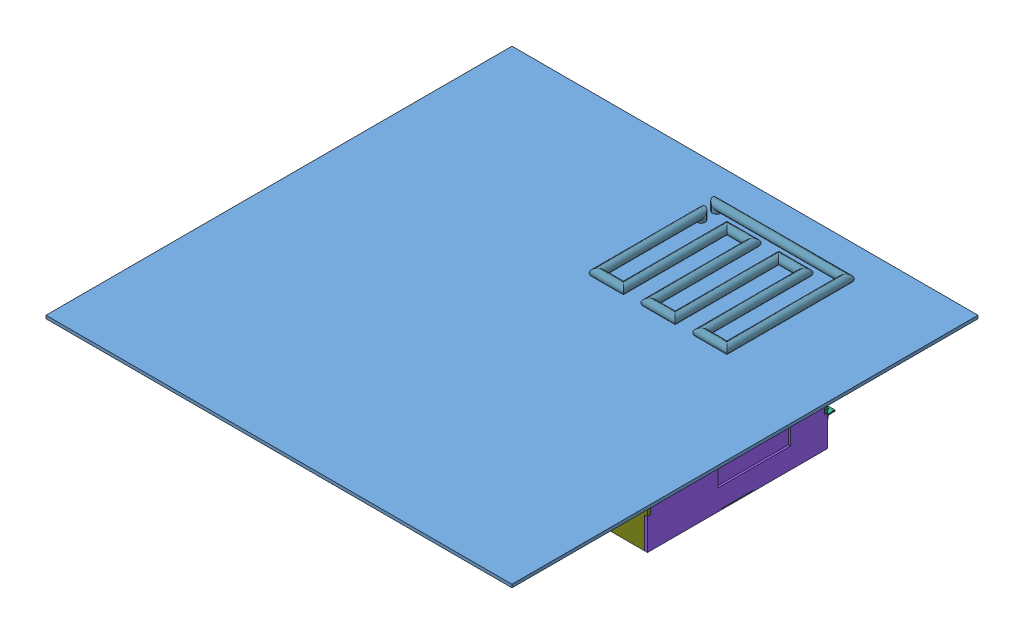
SolidWorks assembly House_Modular, configuration Default. Lengths in mm.
Overall size (450 127.63 450).
180 component instances, 85 part files, 139 mates.
Components (placement in the parent):
- ground-2: ground [Default] at (29.9033 0 -57.0618) x (1 0 0) z (0 1 0) size (450 450 3)
- door-1: door [Default] at (-96.5829 43.9908 -3) x (-1 0 0) z (0 0 1) size (30 61 3)
- door-2: door [Default] at (-38.2325 43.9908 -155.3504) x (0 0 -1) z (-1 0 0) size (30 61 3)
- sg90-1: sg90 [Default] at (138.7675 -45.998 -166.9) x (0 -1 0) z (-1 0 0) size (31.9 29.9 11.8)
- door-3: door [Default] at (-41.2325 43.9908 -18.6496) x (0 0 1) z (1 0 0) size (30 61 3)
- ESP32-CAM-1: ESP32-CAM [Default] at (34.3709 -59.4874 -9.0698) x (1 0 0) z (0 -1 0) size (40.5 18.58 27)
- 25x25x7_fan-1: 25x25x7_fan [Default] at (-17.2845 -26.1253 -169.7289) x (1 0 0) z (0 0 -1) size (25.78 25.81 8)
- TCRT5000-1: TCRT5000 [Predeterminado] at (33.7675 -28.3 -7.5) x (0 -1 0) z (0 0 1) size (14 36.97 13.8)
- bedroom_window-1: bedroom_window [Default] at (-82.9325 -48.4 -2) x (1 0 0) z (0 1 0) size (30 1 21)
- living_room_window-2: living_room_window [Default] at (139.7675 -61.9959 -92.4856) x (0 0 -1) z (0 1 0) size (70 1 25)
- SG90 plastic Horn-1: SG90 plastic Horn [Default] at (132.8675 -51.898 -138.2) x (0.279531 -0.960137 0) z (-0.960137 -0.279531 0) size (19.4 4 7.07)
- irf520n_module_asm-1: irf520n_module_asm [Default] at (0.8196 -70.3815 -175.6) x (-1 0 0) z (0 0 -1) size (34 31 21.5)
  - irf520n_module_asm.stp-1: irf520n_module_asm.stp [Default] at origin size (34 31 21.5)
    - CONECTOR_2X_AF0_ASM.stp-1: CONECTOR_2X_AF0_ASM.stp [Default] at (10.0021 9.5092 -1.5) x (1 0 0) z (0 -1 0) size (10 12.5 7.5)
      - CONEC1_AF0.stp-1: CONEC1_AF0.stp [Default] at origin size (0.5 1 0.5)
      - CONEC2_AF0.stp-1: CONEC2_AF0.stp [Default] at origin size (0.5 1 0.5)
      - CONEC3.stp-1: CONEC3.stp [Default] at origin size (4 2.5 0.5)
      - CONEC4.stp-1: CONEC4.stp [Default] at origin size (4 2.5 0.5)
      - CONEC5.stp-1: CONEC5.stp [Default] at origin size (3.8 3.8 4)
      - CONEC6.stp-1: CONEC6.stp [Default] at origin size (3.8 3.8 4)
      - CONEC7.stp-1: CONEC7.stp [Default] at origin size (10 10 7.5)
      - CONEC8.stp-1: CONEC8.stp [Default] at origin size (2.6 2.5 2.6)
      - CONEC9.stp-1: CONEC9.stp [Default] at origin size (2.6 2.5 2.6)
    - CONECTOR_2X_AF1_ASM.stp-1: CONECTOR_2X_AF1_ASM.stp [Default] at (23.4021 9.5092 -1.5) x (1 0 0) z (0 -1 0) size (10 12.5 7.5)
      - CONEC1_AF1.stp-1: CONEC1_AF1.stp [Default] at origin size (0.5 1 0.5)
      - CONEC2_AF1.stp-1: CONEC2_AF1.stp [Default] at origin size (0.5 1 0.5)
      - CONEC3.stp-1: CONEC3.stp [Default] at origin size (4 2.5 0.5)
      - CONEC4.stp-1: CONEC4.stp [Default] at origin size (4 2.5 0.5)
      - CONEC5.stp-1: CONEC5.stp [Default] at origin size (3.8 3.8 4)
      - CONEC6.stp-1: CONEC6.stp [Default] at origin size (3.8 3.8 4)
      - CONEC7.stp-1: CONEC7.stp [Default] at origin size (10 10 7.5)
      - CONEC8.stp-1: CONEC8.stp [Default] at origin size (2.6 2.5 2.6)
      - CONEC9.stp-1: CONEC9.stp [Default] at origin size (2.6 2.5 2.6)
    - IRF520_AF0_ASM.stp-1: IRF520_AF0_ASM.stp [Default] at (16.0021 9.4375 4) x (0 1 0) z (0 0 1) size (4.75 10.5 21.5)
      - IRF3808_1_AF0_ASM.stp-1: IRF3808_1_AF0_ASM.stp [Default] at origin size (0.55 3.94 6.5)
        - IRF3808_1_1_AF0.stp-1: IRF3808_1_1_AF0.stp [Default] at origin size (0.55 1.4 6.5)
        - IRF3808_1_2_AF0.stp-1: IRF3808_1_2_AF0.stp [Default] at origin size (0.55 1.4 6.5)
      - IRF3808_2_AF0.stp-1: IRF3808_2_AF0.stp [Default] at origin size (0.55 1.4 6.5)
      - IRF3808_3.stp-1: IRF3808_3.stp [Default] at origin size (1.22 10.5 12.3)
      - IRF3808_4.stp-1: IRF3808_4.stp [Default] at origin size (4.53 10.5 8.7)
    - IRF520N.stp-1: IRF520N.stp [Default] at origin size (34 25 1.6)
    - ______________6_AF0.stp-1: ______________6_AF0.stp [Default] at (23.2521 9.2592 -1.5) x (0 1 0) z (1 0 0) size (9.25 7.25 7.5)
    - LED.stp-1: LED.stp [Default] at (23.3771 10.0092 0) x (0 1 0) z (1 0 0) size (4.01 1.01 1.32)
    - 603_RESISTOR.stp-1: 603_RESISTOR.stp [Default] at (20.6021 10.0463 0) x (0 -1 0) z (-1 0 0) size (2.36 0.61 1.02)
    - 603_RESISTOR.stp-2: 603_RESISTOR.stp [Default] at (26.1021 10.0463 0) x (0 -1 0) z (-1 0 0) size (2.36 0.61 1.02)
- irf520n_module_asm-2: irf520n_module_asm [Default] at (133.7196 -84.5092 -175.6) x (-1 0 0) z (0 0 -1) size (34 31 21.5)
  - irf520n_module_asm.stp-1: irf520n_module_asm.stp [Default] at origin size (34 31 21.5)
    - CONECTOR_2X_AF0_ASM.stp-1: CONECTOR_2X_AF0_ASM.stp [Default] at (10.0021 9.5092 -1.5) x (1 0 0) z (0 -1 0) size (10 12.5 7.5)
      - CONEC1_AF0.stp-1: CONEC1_AF0.stp [Default] at origin size (0.5 1 0.5)
      - CONEC2_AF0.stp-1: CONEC2_AF0.stp [Default] at origin size (0.5 1 0.5)
      - CONEC3.stp-1: CONEC3.stp [Default] at origin size (4 2.5 0.5)
      - CONEC4.stp-1: CONEC4.stp [Default] at origin size (4 2.5 0.5)
      - CONEC5.stp-1: CONEC5.stp [Default] at origin size (3.8 3.8 4)
      - CONEC6.stp-1: CONEC6.stp [Default] at origin size (3.8 3.8 4)
      - CONEC7.stp-1: CONEC7.stp [Default] at origin size (10 10 7.5)
      - CONEC8.stp-1: CONEC8.stp [Default] at origin size (2.6 2.5 2.6)
      - CONEC9.stp-1: CONEC9.stp [Default] at origin size (2.6 2.5 2.6)
    - CONECTOR_2X_AF1_ASM.stp-1: CONECTOR_2X_AF1_ASM.stp [Default] at (23.4021 9.5092 -1.5) x (1 0 0) z (0 -1 0) size (10 12.5 7.5)
      - CONEC1_AF1.stp-1: CONEC1_AF1.stp [Default] at origin size (0.5 1 0.5)
      - CONEC2_AF1.stp-1: CONEC2_AF1.stp [Default] at origin size (0.5 1 0.5)
      - CONEC3.stp-1: CONEC3.stp [Default] at origin size (4 2.5 0.5)
      - CONEC4.stp-1: CONEC4.stp [Default] at origin size (4 2.5 0.5)
      - CONEC5.stp-1: CONEC5.stp [Default] at origin size (3.8 3.8 4)
      - CONEC6.stp-1: CONEC6.stp [Default] at origin size (3.8 3.8 4)
      - CONEC7.stp-1: CONEC7.stp [Default] at origin size (10 10 7.5)
      - CONEC8.stp-1: CONEC8.stp [Default] at origin size (2.6 2.5 2.6)
      - CONEC9.stp-1: CONEC9.stp [Default] at origin size (2.6 2.5 2.6)
    - IRF520_AF0_ASM.stp-1: IRF520_AF0_ASM.stp [Default] at (16.0021 9.4375 4) x (0 1 0) z (0 0 1) size (4.75 10.5 21.5)
      - IRF3808_1_AF0_ASM.stp-1: IRF3808_1_AF0_ASM.stp [Default] at origin size (0.55 3.94 6.5)
        - IRF3808_1_1_AF0.stp-1: IRF3808_1_1_AF0.stp [Default] at origin size (0.55 1.4 6.5)
        - IRF3808_1_2_AF0.stp-1: IRF3808_1_2_AF0.stp [Default] at origin size (0.55 1.4 6.5)
      - IRF3808_2_AF0.stp-1: IRF3808_2_AF0.stp [Default] at origin size (0.55 1.4 6.5)
      - IRF3808_3.stp-1: IRF3808_3.stp [Default] at origin size (1.22 10.5 12.3)
      - IRF3808_4.stp-1: IRF3808_4.stp [Default] at origin size (4.53 10.5 8.7)
    - IRF520N.stp-1: IRF520N.stp [Default] at origin size (34 25 1.6)
    - ______________6_AF0.stp-1: ______________6_AF0.stp [Default] at (23.2521 9.2592 -1.5) x (0 1 0) z (1 0 0) size (9.25 7.25 7.5)
    - LED.stp-1: LED.stp [Default] at (23.3771 10.0092 0) x (0 1 0) z (1 0 0) size (4.01 1.01 1.32)
    - 603_RESISTOR.stp-1: 603_RESISTOR.stp [Default] at (20.6021 10.0463 0) x (0 -1 0) z (-1 0 0) size (2.36 0.61 1.02)
    - 603_RESISTOR.stp-2: 603_RESISTOR.stp [Default] at (26.1021 10.0463 0) x (0 -1 0) z (-1 0 0) size (2.36 0.61 1.02)
- Protoboard_with_resistors-1: Protoboard_with_resistors [Default] at (121.7903 -82.1488 -189.9712) x (-1 0 0) z (0 1 0) size (45 19.41 34.07)
  - MINIPROTOBOARD-1: MINIPROTOBOARD [Default] at (20.7748 18.9712 36.8488) size (45 9.5 34)
  - Resistor Carbon Film 0W5 L10.3 D3.8 LD0.77mm Horizontal-1: Resistor Carbon Film 0W5 L10.3 D3.8 LD0.77mm Horizontal [Default] at (29.8566 34.4712 50.6841) x (0.990749 0 -0.135704) z (0 1 0) size (19.83 3.81 9.91)
  - Resistor Carbon Film 0W5 L10.3 D3.8 LD0.77mm Horizontal-2: Resistor Carbon Film 0W5 L10.3 D3.8 LD0.77mm Horizontal [Default] at (29.9349 34.4712 31.1282) x (0.991455 0 -0.130446) z (0 1 0) size (19.83 3.81 9.91)
  - Resistor Carbon Film 0W5 L10.3 D3.8 LD0.77mm Horizontal-3: Resistor Carbon Film 0W5 L10.3 D3.8 LD0.77mm Horizontal [Default] at (29.8373 34.4712 23.175) x (0.991455 0 -0.130446) z (0 1 0) size (19.83 3.81 9.91)
  - Resistor Carbon Film 0W5 L10.3 D3.8 LD0.77mm Horizontal-4: Resistor Carbon Film 0W5 L10.3 D3.8 LD0.77mm Horizontal [Default] at (11.6938 34.4712 50.4431) x (0.991455 0 -0.130446) z (0 1 0) size (19.83 3.81 9.91)
  - Resistor Carbon Film 0W5 L10.3 D3.8 LD0.77mm Horizontal-5: Resistor Carbon Film 0W5 L10.3 D3.8 LD0.77mm Horizontal [Default] at (11.7515 34.4712 42.5299) x (0.991455 0 -0.130446) z (0 1 0) size (19.83 3.81 9.91)
  - Resistor Carbon Film 0W5 L10.3 D3.8 LD0.77mm Horizontal-6: Resistor Carbon Film 0W5 L10.3 D3.8 LD0.77mm Horizontal [Default] at (11.7518 34.4712 31.0334) x (0.991455 0 -0.130446) z (0 1 0) size (19.83 3.81 9.91)
  - Resistor Carbon Film 0W5 L10.3 D3.8 LD0.77mm Horizontal-7: Resistor Carbon Film 0W5 L10.3 D3.8 LD0.77mm Horizontal [Default] at (29.8542 34.4712 42.577) x (0.991455 0 -0.130446) z (0 1 0) size (19.83 3.81 9.91)
  - Resistor Carbon Film 0W5 L10.3 D3.8 LD0.77mm Horizontal-8: Resistor Carbon Film 0W5 L10.3 D3.8 LD0.77mm Horizontal [Default] at (11.664 34.4712 23.3005) x (0.991455 0 -0.130446) z (0 1 0) size (19.83 3.81 9.91)
- Tube-1: Tube [Default] at (-17.5325 -26.3726 -201) x (-1 0 0) z (0 0 1) size (133 43 123)
- Fan adapter-1: Fan adapter [Default] at (-43.5325 17.1277 -171) x (0 -1 0) z (0 0 -1) size (31 31 30)
- front_living_room-1: front_living_room [Default] at (-96.9752 39.2755 -3) x (-1 0 0) z (0 0 1) size (183 90 3)
- Rear_kitchen-1: Rear_kitchen [Default] at (115.9594 -3 -174) size (123 90 3)
- front_room-1: front_room [Default] at (-93.0252 40.9131 -3) x (-1 0 0) z (0 0 1) size (123 90 3)
- kitchen_window-1: kitchen_window [Default] at (-65.8325 -46.7 -173) x (0 1 0) z (-1 0 0) size (30 1 15)
- MQ-2-1: MQ-2 [Default] at (-119.0203 -70.9563 -176.6) x (-1 0 0) z (0 0 1) size (32.25 20.65 21.36)
  - MQ-2.STEP-1: MQ-2.STEP [Default] at origin size (32.25 20.65 21.36)
    - MQ-2.step.STEP-1: MQ-2.step.STEP [Default] at origin size (32.25 20.65 21.36)
      - SMP-generic.step.STEP-1: SMP-generic.step.STEP [Default] at (-6.8415 -4.3705 0.0123) x (-1 0 0) z (0 0 -1) size (7.04 5 1.51)
        - leads.step.STEP-1: leads.step.STEP [Default] at origin size (7.04 4.3 1.25)
        - SMP-generic-0.step.STEP-1: SMP-generic-0.step.STEP [Default] at origin size (4 5 1.5)
      - LED SMT.step.STEP-1: LED SMT.step.STEP [Default] at (0.6625 8.5036 0.1819) x (1 0 0) z (0 0 -1) size (4.65 1.31 0.64)
        - Component1.step.STEP-1: Component1.step.STEP [Default] at (0.0071 0.0115 0.0021) size (2 1.3 0.6)
        - LED SMT-1.step.STEP-1: LED SMT-1.step.STEP [Default] at origin size (1.21 1.3 0.62)
        - LED SMT-2.step.STEP-1: LED SMT-2.step.STEP [Default] at origin size (1.43 1.3 0.63)
        - LED SMT-3.step.STEP-1: LED SMT-3.step.STEP [Default] at origin size (1.09 0.6 0.1)
        - LED SMT-4.step.STEP-1: LED SMT-4.step.STEP [Default] at origin size (1.4 0.58 0.1)
      - LED SMT_1.step.STEP-1: LED SMT_1.step.STEP [Default] at (1.6513 -8.947 0.1758) x (1 0 0) z (0 0 -1) size (4.65 1.31 0.64)
        - Component1.step.STEP-1: Component1.step.STEP [Default] at (0.0071 0.0115 0.0021) size (2 1.3 0.6)
        - LED SMT_1-5.step.STEP-1: LED SMT_1-5.step.STEP [Default] at origin size (1.21 1.3 0.62)
        - LED SMT_1-6.step.STEP-1: LED SMT_1-6.step.STEP [Default] at origin size (1.43 1.3 0.63)
        - LED SMT_1-7.step.STEP-1: LED SMT_1-7.step.STEP [Default] at origin size (1.09 0.6 0.1)
        - LED SMT_1-8.step.STEP-1: LED SMT_1-8.step.STEP [Default] at origin size (1.4 0.58 0.1)
      - small POT.step.STEP-1: small POT.step.STEP [Default] at (-8.8072 6.1022 -0.1215) x (0 1 0) z (0 0 -1) size (7 7 6.25)
        - Component1_1.step.STEP-1: Component1_1.step.STEP [Default] at origin size (7 7 6.25)
        - Component2.step.STEP-1: Component2.step.STEP [Default] at (0 0 -0.101) size (3.49 3.49 1)
      - PCB.step.STEP-1: PCB.step.STEP [Default] at origin size (32.25 20.65 1.6)
      - sensor.step.STEP-1: sensor.step.STEP [Default] at origin size (19.68 19.68 18.01)
      - 10k ohm SMT.step.STEP-1: 10k ohm SMT.step.STEP [Default] at (-6.3738 -9.0701 0.182) x (1 0 0) z (0 0 -1) size (4.65 1.3 0.64)
      - 10k ohm SMT.step.STEP-2: 10k ohm SMT.step.STEP [Default] at (5.9398 -9.0079 0.2021) x (1 0 0) z (0 0 -1) size (4.65 1.3 0.64)
      - 10k ohm SMT.step.STEP-3: 10k ohm SMT.step.STEP [Default] at (-10.6991 1.4157 0.2498) x (-1 0 0) z (0 0 -1) size (4.65 1.3 0.64)
      - 10k ohm SMT.step.STEP-4: 10k ohm SMT.step.STEP [Default] at (12.9889 -2.6781 0.1874) x (1 0 0) z (0 0 -1) size (4.65 1.3 0.64)
      - 10k ohm SMT.step.STEP-5: 10k ohm SMT.step.STEP [Default] at (13.0248 -0.0312 0.1725) x (1 0 0) z (0 0 -1) size (4.65 1.3 0.64)
      - 10k ohm SMT.step.STEP-6: 10k ohm SMT.step.STEP [Default] at (13.1811 2.923 0.1948) x (1 0 0) z (0 0 -1) size (4.65 1.3 0.64)
      - 10k ohm SMT.step.STEP-7: 10k ohm SMT.step.STEP [Default] at (4.9611 8.4811 0.2136) x (1 0 0) z (0 0 -1) size (4.65 1.3 0.64)
- PIR SR602-2: PIR SR602 [Default] at (-39.6325 -100.1412 -80.8303) x (0 0 1) z (0 -1 0) size (16 18.89 16)
- BU-2: BU [Predeterminado] at (-78.4255 -61.637 -182) x (0 1 0) z (0 0 1) size (23.75 15.4 11)
- KY-026_flame_IR_sensor-1: KY-026_flame_IR_sensor [Default] at (-122.6825 -41 -190.03) x (0 0 1) z (0 -1 0) size (44.9 15.1 14.02)
- roof2_single_wall-1: roof2_single_wall [Default] at (-135.0442 -100.5287 -134.2016) x (0 -0.349591 0.936903) z (1 0 0) size (71.51 3 123)
- right_kitchen_outside_single_wall-1: right_kitchen_outside_single_wall [Default] at (-164.2325 134.9698 -393.8578) x (0 0 1) z (1 0 0) size (73 115 3)
- middle_wall_kitchen_single_wall-1: middle_wall_kitchen_single_wall [Default] at (-44.2325 139.1238 -352.6279) x (0 0 1) z (1 0 0) size (73 115 3)
- room_wall_single_wall-1: room_wall_single_wall [Default] at (-94.8313 -26.8319 -104.0015) x (-1 0 0) z (0 1 0) size (123 3 115)
- middle_wall_bedroom_single_wall-1: middle_wall_bedroom_single_wall [Default] at (-44.2325 139.1238 -352.6902) x (0 0 1) z (1 0 0) size (101 115 3)
- room_wall_single_wall-2: room_wall_single_wall [Default] at (-94.8313 -26.8319 -101.0015) x (-1 0 0) z (0 1 0) size (123 3 115)
- left_living_room_single_wall-1: left_living_room_single_wall [Default] at (141.7675 -31.9153 -252.4029) x (0 0 1) z (-1 0 0) size (174 90 3)
- floor_living_room_single_wall-1: floor_living_room_single_wall [Default] at (60.2675 0 -56.3991) x (0 0 1) z (1 0 0) size (174 3 183)
- transparent_roof_living_room_single_wall-1: transparent_roof_living_room_single_wall [Default] at (87.0895 -89 -51.008) x (-1 0 0) z (0 0 1) size (180 1 174)
- middle_wall_living_room_single_wall-2: middle_wall_living_room_single_wall [Default] at (-41.2325 139.1238 -352.1905) x (0 0 1) z (1 0 0) size (174 90 3)
- floor_bedroom_single_wall1-1: floor_bedroom_single_wall1 [Predeterminado] at (-95.0628 -3 -39.2788) x (-1 0 0) z (0 1 0) size (123 101 3)
- floor_kitchen1-1: floor_kitchen1 [Predeterminado] at (-109.3573 0 -137.6238) x (1 0 0) z (0 -1 0) size (123 73 3)
- roof1_v3_single_wall-1: roof1_v3_single_wall [Default] at (-84.9242 -96.7008 -40.251) x (0 0.254493 0.967075) z (1 0 0) size (98.23 3 123)
- Rear_living_room_v1-1: Rear_living_room_v1 [Default] at (113.9094 -6.9472 -174) size (183 90 3)
- Fireplace2-1: Fireplace2 [Predeterminado] at (47.7675 -3 -157.73) x (-1 0 0) z (0 -1 0) size (79 38.67 74.93)
- TV Stand1-1: TV Stand1 [Predeterminado] at (48.7675 -3 -161) x (-1 0 0) z (0 -1 0) size (57 19 21)
- LCD_TFT_1.8_SPI_ST7735-1: LCD_TFT_1.8_SPI_ST7735 [Varsayılan] at (31.7675 -47 -175.6) x (1 0 0) z (0 -1 0) size (58 7 38)
- PWM Mosfet Modul 400W-1: PWM Mosfet Modul 400W [Predeterminado] at (116.6675 -72 -174) x (1 0 0) z (0 0 -1) size (33.5 17 14.1)
  - PWM Mosfet Modul 400W.step-1: PWM Mosfet Modul 400W.step [Predeterminado] at origin size (33.5 17 14.1)
    - Components.step-1: Components.step [Predeterminado] at origin size (29.75 15.18 14.1)
      - r-smd-0603.step-1: r-smd-0603.step [Predeterminado] at (9.281 -4.0736 1.6099) x (0 1 0) z (1 0 0) size (1.6 0.45 0.8)
      - PinHeader.step-1: PinHeader.step [Predeterminado] at (13.55 6.3633 1.6067) x (0 -1 0) z (-1 0 0) size (10.16 11.94 2.54)
      - r-smd-0603.step-2: r-smd-0603.step [Predeterminado] at (7.881 -4.0736 1.6099) x (0 1 0) z (1 0 0) size (1.6 0.45 0.8)
      - r-smd-0603.step-3: r-smd-0603.step [Predeterminado] at (8.603 -1.3259 1.6099) x (1 0 0) z (0 -1 0) size (1.6 0.45 0.8)
      - MOS.step-1: MOS.step [Predeterminado] at (0.2016 -3.5972 0.8) x (0 1 0) z (0 0 1) size (7 10.4 3.01)
      - MOS.step-2: MOS.step [Predeterminado] at (0.2016 4.4028 0.8) x (0 1 0) z (0 0 1) size (7 10.4 3.01)
      - tb5p-2p_p5_l10_w7-6_h10 v1.step-1: tb5p-2p_p5_l10_w7-6_h10 v1.step [Predeterminado] at (-10.6 -4.5 6.6) x (1 0 0) z (0 -1 0) size (10.6 14.1 7.6)
      - tb5p-2p_p5_l10_w7-6_h10 v1.step-2: tb5p-2p_p5_l10_w7-6_h10 v1.step [Predeterminado] at (-10.6316 4.4818 6.6) x (-1 0 0) z (0 1 0) size (10.6 14.1 7.6)
    - PWM Mosfet Modul 400W.step-1: PWM Mosfet Modul 400W.step [Predeterminado] at origin size (33.5 17 1.66)
- PWM Mosfet Modul 400W-2: PWM Mosfet Modul 400W [Predeterminado] at (-16.1325 -57.8723 -174) x (-1 0 0) z (0 0 -1) size (33.5 17 14.1)
  - PWM Mosfet Modul 400W.step-1: PWM Mosfet Modul 400W.step [Predeterminado] at origin size (33.5 17 14.1)
    - Components.step-1: Components.step [Predeterminado] at origin size (29.75 15.18 14.1)
      - r-smd-0603.step-1: r-smd-0603.step [Predeterminado] at (9.281 -4.0736 1.6099) x (0 1 0) z (1 0 0) size (1.6 0.45 0.8)
      - PinHeader.step-1: PinHeader.step [Predeterminado] at (13.55 6.3633 1.6067) x (0 -1 0) z (-1 0 0) size (10.16 11.94 2.54)
      - r-smd-0603.step-2: r-smd-0603.step [Predeterminado] at (7.881 -4.0736 1.6099) x (0 1 0) z (1 0 0) size (1.6 0.45 0.8)
      - r-smd-0603.step-3: r-smd-0603.step [Predeterminado] at (8.603 -1.3259 1.6099) x (1 0 0) z (0 -1 0) size (1.6 0.45 0.8)
      - MOS.step-1: MOS.step [Predeterminado] at (0.2016 -3.5972 0.8) x (0 1 0) z (0 0 1) size (7 10.4 3.01)
      - MOS.step-2: MOS.step [Predeterminado] at (0.2016 4.4028 0.8) x (0 1 0) z (0 0 1) size (7 10.4 3.01)
      - tb5p-2p_p5_l10_w7-6_h10 v1.step-1: tb5p-2p_p5_l10_w7-6_h10 v1.step [Predeterminado] at (-10.6 -4.5 6.6) x (1 0 0) z (0 -1 0) size (10.6 14.1 7.6)
      - tb5p-2p_p5_l10_w7-6_h10 v1.step-2: tb5p-2p_p5_l10_w7-6_h10 v1.step [Predeterminado] at (-10.6316 4.4818 6.6) x (-1 0 0) z (0 1 0) size (10.6 14.1 7.6)
    - PWM Mosfet Modul 400W.step-1: PWM Mosfet Modul 400W.step [Predeterminado] at origin size (33.5 17 1.66)
- 16340_simple_powerbank-1: 16340_simple_powerbank [Default] at (122.5001 23.4903 -152.6323) x (-1 0 0) z (0 -1 0) size (59 22.46 27)
  - 16340_simple_powerbank-1: 16340_simple_powerbank [Default] at (19.9244 21.3677 52.796) size (59 16 27)
  - 16340-1: 16340 [Standard] at (1.7326 35.3281 45.9903) x (0 -1 0) z (0 0 1) size (17 34.5 17)
- ws8212-7-1: ws8212-7 [Predeterminado] at (-165.2325 -94.0121 -83.9487) x (0 1 0) z (1 0 0) size (24 24 3.1)
- right_bedroom_v3_single_wall-1: right_bedroom_v3_single_wall [Default] at (-164.2325 134.9698 -406.6011) x (0 0 1) z (1 0 0) size (101 115 3)
- KY-018_v2-1: KY-018_v2 [Default] at (-150.4362 -83.037 1) x (0 -1 0) z (0 0 1) size (27.44 15 8.55)
  - KY-018.stp-1: KY-018.stp [Default] at origin size (27.44 15 8.55)
    - board.stp-1: board.stp [Default] at (-16.037 -3.7963 -1) size (18 15 2)
    - User Library-PLS-3R.stp-1: User Library-PLS-3R.stp [Default] at (-13.0023 6.2551 0.9782) x (-0.999988 -0.001112 -0.004738) z (-0.001075 0.99997 -0.007711) size (8.62 8.45 7.62)
    - User Library-Photoresistor.stp-1: User Library-Photoresistor.stp [Default] at (6.8069 3.7234 1.2444) x (-0.001332 0.017452 -0.999847) z (0.000098 -0.999848 -0.017452) size (3.91 12.45 4.62)
- Microphone Module-2: Microphone Module [Default] at (-156.2784 -80.8351 -13.7095) x (0 1 0) z (1 0 0) size (42.03 14.59 15)
Mates (geometry in assembly coordinates):
- Coincident114: coincident anti-aligned: plane of ground-2 through (29.9033 0 -57.0618) normal (0 -1 0); plane of assembly through (0 0 0) normal (0 1 0)
- Concentric17: concentric aligned: circle of sg90-1; circle of SG90 plastic Horn-1
- Coincident309: coincident anti-aligned: plane of sg90-1 through (177.5105 -51.898 -140.2) normal (0 0 1); plane of SG90 plastic Horn-1 through (178.1744 -54.1783 -140.2) normal (0 0 -1)
- Coincident393: coincident anti-aligned: plane of 25x25x7_fan-1 through (37.6085 -38.8753 -171) normal (0 -1 0); plane of Fan adapter-1 through (1.1105 -38.8753 -171) normal (0 1 0)
- Coincident394: coincident anti-aligned: plane of 25x25x7_fan-1 through (14.6085 -26.1253 -171) normal (-1 0 0); plane of Fan adapter-1 through (14.6085 17.1277 -171) normal (1 0 0)
- Coincident395: coincident aligned: plane of 25x25x7_fan-1 through (27.3585 -26.1253 -171) normal (0 0 1); plane of Fan adapter-1 through (1.1105 17.1277 -171) normal (0 0 1)
- Concentric24: concentric anti-aligned: circle of Tube-1; circle of Fan adapter-1
- Coincident438: coincident anti-aligned: plane of door-1 through (43.4105 -61 0) normal (0 -1 0); plane of front_living_room-1 through (73.4105 -61 0) normal (0 1 0)
- Coincident439: coincident anti-aligned: plane of door-1 through (73.4105 -61 0) normal (1 0 0); plane of front_living_room-1 through (73.4105 0 0) normal (-1 0 0)
- Concentric27: concentric anti-aligned: circle of ESP32-CAM-1; circle of front_living_room-1
- Coincident478: coincident aligned: plane of front_living_room-1 through (-52.3322 39.2755 0) normal (0 0 1); plane of front_room-1 through (-48.3822 40.9131 0) normal (0 0 1)
- Coincident479: coincident aligned: plane of front_living_room-1 through (3.4105 -90 0) normal (0 -1 0); plane of front_room-1 through (-116.5895 -90 0) normal (0 -1 0)
- Coincident480: coincident anti-aligned: plane of front_living_room-1 through (3.4105 -60 0) normal (-1 0 0); plane of front_room-1 through (3.4105 -60 0) normal (1 0 0)
- Coincident503: coincident anti-aligned: plane of Rear_kitchen-1 through (-14.5895 -30 -171) normal (0 -1 0); plane of kitchen_window-1 through (-14.5895 -30 -174) normal (0 1 0)
- Coincident505: coincident anti-aligned: plane of Rear_kitchen-1 through (-14.5895 -60 -171) normal (-1 0 0); plane of kitchen_window-1 through (-14.5895 -60 -174) normal (1 0 0)
- Concentric40: concentric aligned: circle of Rear_kitchen-1; circle of BU-2
- Parallel34: parallel aligned: plane of Rear_kitchen-1 through (3.4105 -90 -171) normal (0 -1 0); plane of BU-2 through (-33.7825 -80.75 -181) normal (0 -1 0)
- Coincident545: coincident aligned: plane of Rear_kitchen-1 through (160.6024 -3 -171) normal (0 0 1); plane of BU-2 through (-38.5895 -71 -171) normal (0 0 1)
- Coincident546: coincident anti-aligned: plane of Rear_kitchen-1 through (-85.5895 -41 -171) normal (0 -1 0); plane of KY-026_flame_IR_sensor-1 through (-78.079 -41 -187.3371) normal (0 1 0)
- Coincident547: coincident anti-aligned: plane of Rear_kitchen-1 through (-85.5895 -43 -171) normal (1 0 0); plane of KY-026_flame_IR_sensor-1 through (-85.5895 -41 -205.7414) normal (-1 0 0)
- Coincident591: coincident aligned: plane of Rear_kitchen-1 through (-119.5895 -60 -171) normal (-1 0 0); plane of right_kitchen_outside_single_wall-1 through (-119.5895 134.9698 -393.8578) normal (-1 0 0)
- Coincident592: coincident aligned: plane of Rear_kitchen-1 through (3.4105 -90 -171) normal (0 -1 0); plane of right_kitchen_outside_single_wall-1 through (-116.5895 -90 -174) normal (0 -1 0)
- Coincident593: coincident aligned: plane of Rear_kitchen-1 through (160.6024 -3 -174) normal (0 0 -1); plane of right_kitchen_outside_single_wall-1 through (-116.5895 -60 -174) normal (0 0 -1)
- Coincident596: coincident anti-aligned: plane of Rear_kitchen-1 through (3.4105 -30 -171) normal (0 -1 0); plane of middle_wall_kitchen_single_wall-1 through (3.4105 -30 -171) normal (0 1 0)
- Coincident598: coincident anti-aligned: plane of roof2_single_wall-1 through (0.4105 -97.2561 -151.5535) normal (0 0.349591 -0.936903); plane of middle_wall_kitchen_single_wall-1 through (3.4105 -97.2561 -151.5535) normal (0 -0.349591 0.936903)
- Coincident599: coincident anti-aligned: plane of roof2_single_wall-1 through (-90.4012 -100.5287 -134.2016) normal (0 0.936903 0.349591); plane of middle_wall_kitchen_single_wall-1 through (3.4105 -104.9332 -122.3977) normal (0 -0.936903 -0.349591)
- Coincident600: coincident aligned: plane of roof2_single_wall-1 through (3.4105 -97.2561 -151.5535) normal (1 0 0); plane of middle_wall_kitchen_single_wall-1 through (3.4105 139.1238 -352.6279) normal (1 0 0)
- Coincident602: coincident aligned: plane of right_kitchen_outside_single_wall-1 through (-116.5895 -115 -101.0015) normal (0 -1 0); plane of room_wall_single_wall-1 through (0.4105 -115 -101.0015) normal (0 -1 0)
- Coincident603: coincident aligned: plane of right_kitchen_outside_single_wall-1 through (-119.5895 134.9698 -393.8578) normal (-1 0 0); plane of room_wall_single_wall-1 through (-119.5895 -60 -101.0015) normal (-1 0 0)
- Coincident604: coincident aligned: plane of right_kitchen_outside_single_wall-1 through (-116.5895 -30 -101.0015) normal (0 0 1); plane of room_wall_single_wall-1 through (-50.1883 -26.8319 -101.0015) normal (0 0 1)
- Coincident608: coincident aligned: plane of front_living_room-1 through (-52.3322 39.2755 0) normal (0 0 1); plane of middle_wall_bedroom_single_wall-1 through (3.4105 -60 0) normal (0 0 1)
- Coincident609: coincident anti-aligned: plane of front_room-1 through (3.4105 -60 0) normal (0 1 0); plane of middle_wall_bedroom_single_wall-1 through (3.4105 -60 -3) normal (0 -1 0)
- Coincident610: coincident aligned: plane of middle_wall_kitchen_single_wall-1 through (3.4105 139.1238 -352.6279) normal (1 0 0); plane of middle_wall_bedroom_single_wall-1 through (3.4105 139.1238 -352.6902) normal (1 0 0)
- Coincident616: coincident aligned: plane of front_living_room-1 through (186.4105 -30 0) normal (1 0 0); plane of left_living_room_single_wall-1 through (186.4105 -31.9153 -252.4029) normal (1 0 0)
- Coincident617: coincident anti-aligned: plane of front_living_room-1 through (183.4105 -30 0) normal (0 1 0); plane of left_living_room_single_wall-1 through (183.4105 -30 -3) normal (0 -1 0)
- Coincident618: coincident aligned: plane of front_living_room-1 through (-52.3322 39.2755 0) normal (0 0 1); plane of left_living_room_single_wall-1 through (183.4105 -90 0) normal (0 0 1)
- Coincident623: coincident aligned: plane of door-1 through (-51.94 43.9908 0) normal (0 0 1); plane of front_living_room-1 through (-52.3322 39.2755 0) normal (0 0 1)
- Coincident624: coincident: line of TCRT5000-1 through (84.2105 -40.5 -3) axis (-1 0 0); plane of front_living_room-1 through (-52.3322 39.2755 -3) normal (0 0 -1)
- Parallel39: parallel aligned: plane of TCRT5000-1 through (78.4105 -42.3 -7.5) normal (0 -1 0); plane of front_living_room-1 through (109.9105 -90 0) normal (0 -1 0)
- Coincident627: coincident anti-aligned: plane of TCRT5000-1 through (78.4105 -40.5 -7.5) normal (0 -1 0); plane of front_living_room-1 through (84.4105 -40.5 0) normal (0 1 0)
- Coincident628: coincident anti-aligned: plane of TCRT5000-1 through (78.4105 -28.3 -7.5) normal (-1 0 0); plane of front_living_room-1 through (78.4105 -40.5 0) normal (1 0 0)
- Coincident639: coincident aligned: plane of front_living_room-1 through (-52.3322 39.2755 0) normal (0 0 1); plane of transparent_roof_living_room_single_wall-1 through (79.9105 -90 0) normal (0 0 1)
- Coincident640: coincident aligned: plane of left_living_room_single_wall-1 through (186.4105 -31.9153 -252.4029) normal (1 0 0); plane of transparent_roof_living_room_single_wall-1 through (186.4105 -90 -102) normal (1 0 0)
- Coincident641: coincident anti-aligned: plane of left_living_room_single_wall-1 through (183.4105 -89 -72) normal (0 -1 0); plane of transparent_roof_living_room_single_wall-1 through (131.7325 -89 -51.008) normal (0 1 0)
- Coincident646: coincident anti-aligned: plane of middle_wall_kitchen_single_wall-1 through (0.4105 139.1238 -352.6279) normal (-1 0 0); plane of room_wall_single_wall-1 through (0.4105 -60 -101.0015) normal (1 0 0)
- Coincident647: coincident aligned: plane of Rear_kitchen-1 through (160.6024 -3 -171) normal (0 0 1); plane of KY-026_flame_IR_sensor-1 through (-73.4895 -41 -171) normal (0 0 1)
- Concentric41: concentric aligned: circle of PIR SR602-2; circle of middle_wall_bedroom_single_wall-1
- Coincident648: coincident aligned: plane of Rear_kitchen-1 through (160.6024 -3 -174) normal (0 0 -1); plane of kitchen_window-1 through (-21.1895 -46.7 -174) normal (0 0 -1)
- Coincident649: coincident aligned: plane of living_room_window-2 through (183.4105 -61.9959 -92.4856) normal (-1 0 0); plane of left_living_room_single_wall-1 through (183.4105 -31.9153 -252.4029) normal (-1 0 0)
- Coincident650: coincident anti-aligned: plane of living_room_window-2 through (183.4105 -70 -68) normal (0 0 1); plane of left_living_room_single_wall-1 through (183.4105 -45 -68) normal (0 0 -1)
- Coincident651: coincident anti-aligned: plane of living_room_window-2 through (183.4105 -45 -68) normal (0 1 0); plane of left_living_room_single_wall-1 through (183.4105 -45 -138) normal (0 -1 0)
- Coincident652: coincident anti-aligned: plane of sg90-1 through (183.4105 -45.998 -166.9) normal (1 0 0); plane of left_living_room_single_wall-1 through (183.4105 -31.9153 -252.4029) normal (-1 0 0)
- Coincident653: coincident aligned: plane of ESP32-CAM-1 through (90.4105 -73 0) normal (0 0 1); plane of front_living_room-1 through (-52.3322 39.2755 0) normal (0 0 1)
- Coincident664: coincident anti-aligned: plane of PIR SR602-2 through (3.4105 -100.1412 -88.8303) normal (-1 0 0); plane of middle_wall_bedroom_single_wall-1 through (3.4105 139.1238 -352.6902) normal (1 0 0)
- Coincident666: coincident anti-aligned: plane of bedroom_window-1 through (-51.5895 -61 -3) normal (0 -1 0); plane of front_room-1 through (-21.5895 -61 0) normal (0 1 0)
- Coincident667: coincident anti-aligned: plane of bedroom_window-1 through (-21.5895 -61 -3) normal (1 0 0); plane of front_room-1 through (-21.5895 -40 0) normal (-1 0 0)
- Coincident669: coincident aligned: plane of bedroom_window-1 through (-38.2895 -48.4 -3) normal (0 0 -1); plane of front_room-1 through (-48.3822 40.9131 -3) normal (0 0 -1)
- Coincidente8: coincident anti-aligned: plane of left_living_room_single_wall-1 through (183.4105 -31.9153 -252.4029) normal (-1 0 0); plane of floor_living_room_single_wall-1 through (183.4105 -3 -82) normal (1 0 0)
- Coincidente9: coincident aligned: plane of front_living_room-1 through (-52.3322 39.2755 0) normal (0 0 1); plane of floor_living_room_single_wall-1 through (165.4105 -3 0) normal (0 0 1)
- Coincidente10: coincident aligned: plane of front_living_room-1 through (163.4105 0 0) normal (0 1 0); plane of floor_living_room_single_wall-1 through (104.9105 0 -56.3991) normal (0 1 0)
- Coincidente11: coincident anti-aligned: plane of room_wall_single_wall-1 through (-50.1883 -26.8319 -101.0015) normal (0 0 1); plane of room_wall_single_wall-2 through (-50.1883 -26.8319 -101.0015) normal (0 0 -1)
- Coincidente14: coincident aligned: plane of front_room-1 through (-17.5895 0 0) normal (0 1 0); plane of floor_bedroom_single_wall1-1 through (-50.4198 0 -39.2788) normal (0 1 0)
- Coincidente17: coincident aligned: plane of front_room-1 through (-48.3822 40.9131 0) normal (0 0 1); plane of floor_bedroom_single_wall1-1 through (-98.5895 0 0) normal (0 0 1)
- Coincidente18: coincident aligned: plane of right_kitchen_outside_single_wall-1 through (-119.5895 134.9698 -393.8578) normal (-1 0 0); plane of floor_kitchen1-1 through (-119.5895 -3 -153) normal (-1 0 0)
- Coincidente19: coincident aligned: plane of right_kitchen_outside_single_wall-1 through (-116.5895 0 -163) normal (0 1 0); plane of floor_kitchen1-1 through (-64.7143 0 -137.6238) normal (0 1 0)
- Coincidente20: coincident aligned: plane of Rear_kitchen-1 through (160.6024 -3 -174) normal (0 0 -1); plane of floor_kitchen1-1 through (-108.5895 -3 -174) normal (0 0 -1)
- Coincidente22: coincident anti-aligned: plane of door-2 through (3.4105 -61 -60) normal (0 -1 0); plane of middle_wall_living_room_single_wall-2 through (6.4105 -61 -30) normal (0 1 0)
- Coincidente30: coincident aligned: plane of middle_wall_bedroom_single_wall-1 through (3.4105 139.1238 -352.6902) normal (1 0 0); plane of roof1_v3_single_wall-1 through (3.4105 -106.3174 -65.0061) normal (1 0 0)
- Coincidente31: coincident anti-aligned: plane of middle_wall_bedroom_single_wall-1 through (3.4105 -98.6826 -35.9939) normal (0 -0.254493 -0.967075); plane of roof1_v3_single_wall-1 through (0.4105 -98.6826 -35.9939) normal (0 0.254493 0.967075)
- Concéntrica1: concentric anti-aligned: circle of Rear_kitchen-1; circle of MQ-2-1/MQ-2.STEP-1/MQ-2.step.STEP-1/sensor.step.STEP-1
- Distancia4: distance = 1 mm anti-aligned: plane of MQ-2-1/MQ-2.STEP-1/MQ-2.step.STEP-1/PCB.step.STEP-1 through (-119.0203 -70.9563 -175) normal (0 0 1); plane of Rear_kitchen-1 through (115.9594 -3 -174) normal (0 0 -1)
- Paralelo1: parallel aligned: plane of Rear_kitchen-1 through (3.4105 -90 -171) normal (0 -1 0); plane of MQ-2-1/MQ-2.STEP-1/MQ-2.step.STEP-1/PCB.step.STEP-1 through (-90.5024 -81.2813 -176.6) normal (0 -1 0)
- Coincidente38: coincident anti-aligned: plane of Tube-1 through (-17.5325 -26.3726 -220.1762) normal (0 0 1); plane of Fan adapter-1 through (1.1105 17.1277 -201) normal (0 0 -1)
- Coincidente41: coincident aligned: plane of Rear_kitchen-1 through (160.6024 -3 -174) normal (0 0 -1); plane of Rear_living_room_v1-1 through (158.5524 -6.9472 -174) normal (0 0 -1)
- Coincidente42: coincident aligned: plane of floor_living_room_single_wall-1 through (104.9105 0 -56.3991) normal (0 1 0); plane of Rear_living_room_v1-1 through (21.4105 0 -171) normal (0 1 0)
- Coincidente43: coincident anti-aligned: plane of Rear_kitchen-1 through (3.4105 -60 -171) normal (1 0 0); plane of Rear_living_room_v1-1 through (3.4105 -60 -171) normal (-1 0 0)
- Coincidente44: coincident anti-aligned: plane of left_living_room_single_wall-1 through (183.4105 -30 -171) normal (0 0 -1); plane of Rear_living_room_v1-1 through (158.5524 -6.9472 -171) normal (0 0 1)
- Coincidente45: coincident aligned: plane of left_living_room_single_wall-1 through (186.4105 -31.9153 -252.4029) normal (1 0 0); plane of Rear_living_room_v1-1 through (186.4105 -30 -171) normal (1 0 0)
- Distancia5: distance = 28.3 mm aligned: plane of Protoboard_with_resistors-1/MINIPROTOBOARD-1 through (78.5155 -28.3 -161.5) normal (0 1 0); plane of floor_living_room_single_wall-1 through (60.2675 0 -56.3991) normal (0 1 0)
- Coincidente48: coincident anti-aligned: plane of Protoboard_with_resistors-1/MINIPROTOBOARD-1 through (145.6585 -45.3 -171) normal (0 0 -1); plane of Rear_living_room_v1-1 through (158.5524 -6.9472 -171) normal (0 0 1)
- Coincidente50: coincident anti-aligned: plane of Rear_living_room_v1-1 through (158.5524 -6.9472 -171) normal (0 0 1); plane of Fireplace2-1 through (92.4105 -3 -171) normal (0 0 -1)
- Coincidente51: coincident anti-aligned: plane of floor_living_room_single_wall-1 through (104.9105 -3 -56.3991) normal (0 -1 0); plane of Fireplace2-1 through (104.4105 -3 -151) normal (0 1 0)
- Coincidente52: coincident anti-aligned: plane of left_living_room_single_wall-1 through (183.4105 -31.9153 -252.4029) normal (-1 0 0); plane of Fireplace2-1 through (183.4105 -3 -151) normal (1 0 0)
- Distancia7: distance = 0.5 mm anti-aligned: plane of Protoboard_with_resistors-1/MINIPROTOBOARD-1 through (78.5155 -28.3 -161.5) normal (-1 0 0); plane of Fireplace2-1 through (78.0155 -63.753 -132.33) normal (1 0 0)
- Paralelo2: parallel anti-aligned: plane of sg90-1 through (171.6105 -45.998 -166.9) normal (-1 0 0); plane of Fireplace2-1 through (171.4085 -45.998 -171) normal (1 0 0)
- Coincidente55: coincident anti-aligned: plane of sg90-1 through (171.6105 -45.998 -166.9) normal (0 1 0); plane of Fireplace2-1 through (183.4105 -45.998 -171) normal (0 -1 0)
- Coincidente56: coincident anti-aligned: plane of sg90-1 through (171.6105 -73.198 -151) normal (0 0 -1); plane of Fireplace2-1 through (92.4105 -3 -151) normal (0 0 1)
- Coincidente57: coincident anti-aligned: plane of Rear_living_room_v1-1 through (158.5524 -6.9472 -171) normal (0 0 1); plane of TV Stand1-1 through (93.4105 -3 -171) normal (0 0 -1)
- Coincidente58: coincident anti-aligned: plane of floor_living_room_single_wall-1 through (104.9105 -3 -56.3991) normal (0 -1 0); plane of TV Stand1-1 through (47.4105 -3 -154) normal (0 1 0)
- Coincidente59: coincident anti-aligned: plane of Fireplace2-1 through (104.4105 -77.927 -151) normal (-1 0 0); plane of TV Stand1-1 through (104.4105 -3 -154) normal (1 0 0)
- Coincidente60: coincident anti-aligned: plane of Rear_living_room_v1-1 through (53.9105 -66 -171) normal (0 1 0); plane of LCD_TFT_1.8_SPI_ST7735-1 through (53.9105 -66 -171.6) normal (0 -1 0)
- Coincidente61: coincident anti-aligned: plane of Rear_living_room_v1-1 through (158.5524 -6.9472 -174) normal (0 0 -1); plane of LCD_TFT_1.8_SPI_ST7735-1 through (76.4105 -47 -174) normal (0 0 1)
- Coincidente62: coincident anti-aligned: plane of Rear_living_room_v1-1 through (97.4105 -28 -171) normal (-1 0 0); plane of LCD_TFT_1.8_SPI_ST7735-1 through (97.4105 -28 -171.6) normal (1 0 0)
- Coincidente64: coincident aligned: plane of door-3 through (6.4105 0 -144) normal (0 1 0); plane of floor_living_room_single_wall-1 through (104.9105 0 -56.3991) normal (0 1 0)
- Coincidente65: coincident anti-aligned: plane of door-3 through (6.4105 0 -114) normal (0 0 1); plane of middle_wall_living_room_single_wall-2 through (6.4105 0 -114) normal (0 0 -1)
- Coincidente66: coincident aligned: plane of front_living_room-1 through (-52.3322 39.2755 0) normal (0 0 1); plane of middle_wall_living_room_single_wall-2 through (6.4105 -60 0) normal (0 0 1)
- Coincidente67: coincident aligned: plane of front_living_room-1 through (3.4105 -90 0) normal (0 -1 0); plane of middle_wall_living_room_single_wall-2 through (6.4105 -90 -171) normal (0 -1 0)
- Coincidente68: coincident anti-aligned: plane of middle_wall_bedroom_single_wall-1 through (3.4105 139.1238 -352.6902) normal (1 0 0); plane of middle_wall_living_room_single_wall-2 through (3.4105 139.1238 -352.1905) normal (-1 0 0)
- Coincidente69: coincident anti-aligned: plane of door-2 through (3.4105 -61 -30) normal (0 0 1); plane of middle_wall_living_room_single_wall-2 through (6.4105 0 -30) normal (0 0 -1)
- Coincidente70: coincident anti-aligned: plane of Rear_living_room_v1-1 through (158.5524 -6.9472 -174) normal (0 0 -1); plane of PWM Mosfet Modul 400W-1/PWM Mosfet Modul 400W.step-1/PWM Mosfet Modul 400W.step-1 through (161.3105 -72 -174) normal (0 0 1)
- Concéntrica2: concentric aligned: circle of irf520n_module_asm-2/irf520n_module_asm.stp-1/IRF520N.stp-1; circle of Rear_living_room_v1-1
- Paralelo3: parallel aligned: plane of irf520n_module_asm-2/irf520n_module_asm.stp-1/IRF520N.stp-1 through (176.3605 -84.5 -175.6) normal (0 -1 0); plane of Rear_living_room_v1-1 through (183.4105 -90 -171) normal (0 -1 0)
- Coincidente72: coincident anti-aligned: plane of irf520n_module_asm-2/irf520n_module_asm.stp-1/IRF520N.stp-1 through (178.3625 -84.5092 -174) normal (0 0 1); plane of Rear_living_room_v1-1 through (158.5524 -6.9472 -174) normal (0 0 -1)
- Concéntrica3: concentric aligned: circle of Rear_living_room_v1-1; circle of PWM Mosfet Modul 400W-1/PWM Mosfet Modul 400W.step-1/PWM Mosfet Modul 400W.step-1
- Paralelo4: parallel aligned: plane of Rear_living_room_v1-1 through (183.4105 -90 -171) normal (0 -1 0); plane of PWM Mosfet Modul 400W-1/PWM Mosfet Modul 400W.step-1/PWM Mosfet Modul 400W.step-1 through (178.0605 -80.5 -174) normal (0 -1 0)
- Concéntrica5: concentric aligned: circle of irf520n_module_asm-1/irf520n_module_asm.stp-1/IRF520N.stp-1; circle of Rear_living_room_v1-1
- Coincidente76: coincident anti-aligned: plane of irf520n_module_asm-1/irf520n_module_asm.stp-1/IRF520N.stp-1 through (45.4625 -70.3815 -174) normal (0 0 1); plane of Rear_living_room_v1-1 through (158.5524 -6.9472 -174) normal (0 0 -1)
- Paralelo5: parallel aligned: plane of irf520n_module_asm-1/irf520n_module_asm.stp-1/IRF520N.stp-1 through (43.4605 -70.3723 -175.6) normal (0 -1 0); plane of Rear_living_room_v1-1 through (79.9105 -90 -171) normal (0 -1 0)
- Coincidente78: coincident anti-aligned: plane of Rear_living_room_v1-1 through (158.5524 -6.9472 -174) normal (0 0 -1); plane of PWM Mosfet Modul 400W-2/PWM Mosfet Modul 400W.step-1/PWM Mosfet Modul 400W.step-1 through (28.5105 -57.8723 -174) normal (0 0 1)
- Paralelo6: parallel aligned: plane of Rear_living_room_v1-1 through (79.9105 -90 -171) normal (0 -1 0); plane of PWM Mosfet Modul 400W-2/PWM Mosfet Modul 400W.step-1/PWM Mosfet Modul 400W.step-1 through (45.2605 -66.3723 -174) normal (0 -1 0)
- Concéntrica6: concentric aligned: circle of Rear_living_room_v1-1; circle of PWM Mosfet Modul 400W-2/PWM Mosfet Modul 400W.step-1/PWM Mosfet Modul 400W.step-1
- Coincidente81: coincident anti-aligned: plane of Rear_living_room_v1-1 through (158.5524 -6.9472 -174) normal (0 0 -1); plane of 16340_simple_powerbank-1/16340_simple_powerbank-1 through (147.2187 -29.3057 -174) normal (0 0 1)
- Paralelo7: parallel aligned: plane of floor_living_room_single_wall-1 through (104.9105 0 -56.3991) normal (0 1 0); plane of 16340_simple_powerbank-1/16340_simple_powerbank-1 through (165.4105 -13.5 -182) normal (0 1 0)
- Coincidente83: coincident aligned: plane of room_wall_single_wall-1 through (0.4105 -115 -101.0015) normal (0 -1 0); plane of room_wall_single_wall-2 through (0.4105 -115 -98.0015) normal (0 -1 0)
- Coincidente86: coincident aligned: plane of floor_bedroom_single_wall1-1 through (-50.4198 0 -39.2788) normal (0 1 0); plane of right_bedroom_v3_single_wall-1 through (-116.5895 0 -21) normal (0 1 0)
- Coincidente87: coincident aligned: plane of front_room-1 through (-48.3822 40.9131 0) normal (0 0 1); plane of right_bedroom_v3_single_wall-1 through (-116.5895 -90 0) normal (0 0 1)
- Coincidente89: coincident aligned: plane of front_room-1 through (-119.5895 -60 0) normal (-1 0 0); plane of right_bedroom_v3_single_wall-1 through (-119.5895 134.9698 -406.6011) normal (-1 0 0)
- Coincidente90: coincident anti-aligned: plane of ws8212-7-1 through (-119.5895 -94.0121 -83.9487) normal (1 0 0); plane of right_bedroom_v3_single_wall-1 through (-119.5895 134.9698 -406.6011) normal (-1 0 0)
- Concéntrica8: concentric aligned: circle of ws8212-7-1; circle of right_bedroom_v3_single_wall-1
- Coincidente91: coincident anti-aligned: plane of front_room-1 through (-48.3822 40.9131 0) normal (0 0 1); plane of KY-018_v2-1/KY-018.stp-1/board.stp-1 through (-102.0895 -76 0) normal (0 0 -1)
- Paralelo9: parallel aligned: plane of front_room-1 through (-116.5895 -90 0) normal (0 -1 0); plane of KY-018_v2-1/KY-018.stp-1/board.stp-1 through (-109.5895 -85 0) normal (0 -1 0)
- Paralelo10: parallel aligned: plane of right_bedroom_v3_single_wall-1 through (-119.5895 134.9698 -406.6011) normal (-1 0 0); plane of KY-018_v2-1/KY-018.stp-1/board.stp-1 through (-109.5895 -67 0) normal (-1 0 0)
- Coincidente94: coincident anti-aligned: plane of front_room-1 through (-48.3822 40.9131 0) normal (0 0 1); plane of Microphone Module-2 through (-82.0895 -50 0) normal (0 0 -1)
- Paralelo11: parallel aligned: plane of front_room-1 through (-116.5895 -90 0) normal (0 -1 0); plane of Microphone Module-2 through (-74.5895 -85 0.8) normal (0 -1 0)
- Paralelo12: parallel aligned: plane of right_bedroom_v3_single_wall-1 through (-119.5895 134.9698 -406.6011) normal (-1 0 0); plane of Microphone Module-2 through (-89.5895 -85 0.8) normal (-1 0 0)
- Concéntrica9: concentric anti-aligned: cylinder of front_room-1 through (-82.0895 -58.5 0) axis (0 0 -1) radius 1.5; circle of Microphone Module-2
- Coincidente97: coincident anti-aligned: plane of Fan adapter-1 through (42.6105 17.1277 -171) normal (1 0 0); plane of Rear_living_room_v1-1 through (42.6105 -41.8723 -171) normal (-1 0 0)
- Coincidente98: coincident anti-aligned: plane of Fan adapter-1 through (1.1105 -41.8723 -171) normal (0 -1 0); plane of Rear_living_room_v1-1 through (42.6105 -41.8723 -171) normal (0 1 0)
- Coincidente99: coincident aligned: plane of Fan adapter-1 through (1.1105 17.1277 -171) normal (0 0 1); plane of Rear_living_room_v1-1 through (158.5524 -6.9472 -171) normal (0 0 1)
- Coincidente100: coincident anti-aligned: plane of floor_living_room_single_wall-1 through (3.4105 -3 -11) normal (-1 0 0); plane of floor_bedroom_single_wall1-1 through (3.4105 0 -21) normal (1 0 0)
- Coincidente101: coincident anti-aligned: plane of middle_wall_bedroom_single_wall-1 through (0.4105 139.1238 -352.6902) normal (-1 0 0); plane of room_wall_single_wall-2 through (0.4105 -60 -98.0015) normal (1 0 0)
- Coincidente102: coincident aligned: plane of KY-018_v2-1/KY-018.stp-1/board.stp-1 through (-109.5895 -85 0) normal (0 -1 0); plane of Microphone Module-2 through (-86.5895 -85 0.8) normal (0 -1 0)
- Distancia8: distance = 10 mm aligned: plane of KY-018_v2-1/KY-018.stp-1/board.stp-1 through (-154.2325 -67 0) normal (-1 0 0); plane of right_bedroom_v3_single_wall-1 through (-164.2325 134.9698 -406.6011) normal (-1 0 0)
- Coincidente104: coincident aligned: plane of door-2 through (6.4105 43.9908 -155.3504) normal (1 0 0); plane of middle_wall_living_room_single_wall-2 through (6.4105 139.1238 -352.1905) normal (1 0 0)
- Coincidente105: coincident aligned: plane of door-3 through (6.4105 43.9908 -18.6496) normal (1 0 0); plane of middle_wall_living_room_single_wall-2 through (6.4105 139.1238 -352.1905) normal (1 0 0)
- Concéntrica10: concentric anti-aligned: circle of Rear_living_room_v1-1; circle of 16340_simple_powerbank-1/16340_simple_powerbank-1
- Coincidente106: coincident aligned: plane of floor_bedroom_single_wall1-1 through (-50.4198 0 -39.2788) normal (0 1 0); plane of floor_kitchen1-1 through (-64.7143 0 -137.6238) normal (0 1 0)
- Coincidente108: coincident anti-aligned: plane of ground-2 through (29.9033 0 -57.0618) normal (0 -1 0); plane of floor_living_room_single_wall-1 through (104.9105 0 -56.3991) normal (0 1 0)
- Paralelo15: parallel aligned: plane of ground-2 through (29.9033 0 -57.0618) normal (0 -1 0); plane of Tube-1 through (-17.5325 -26.3726 -226) normal (0 -1 0)
